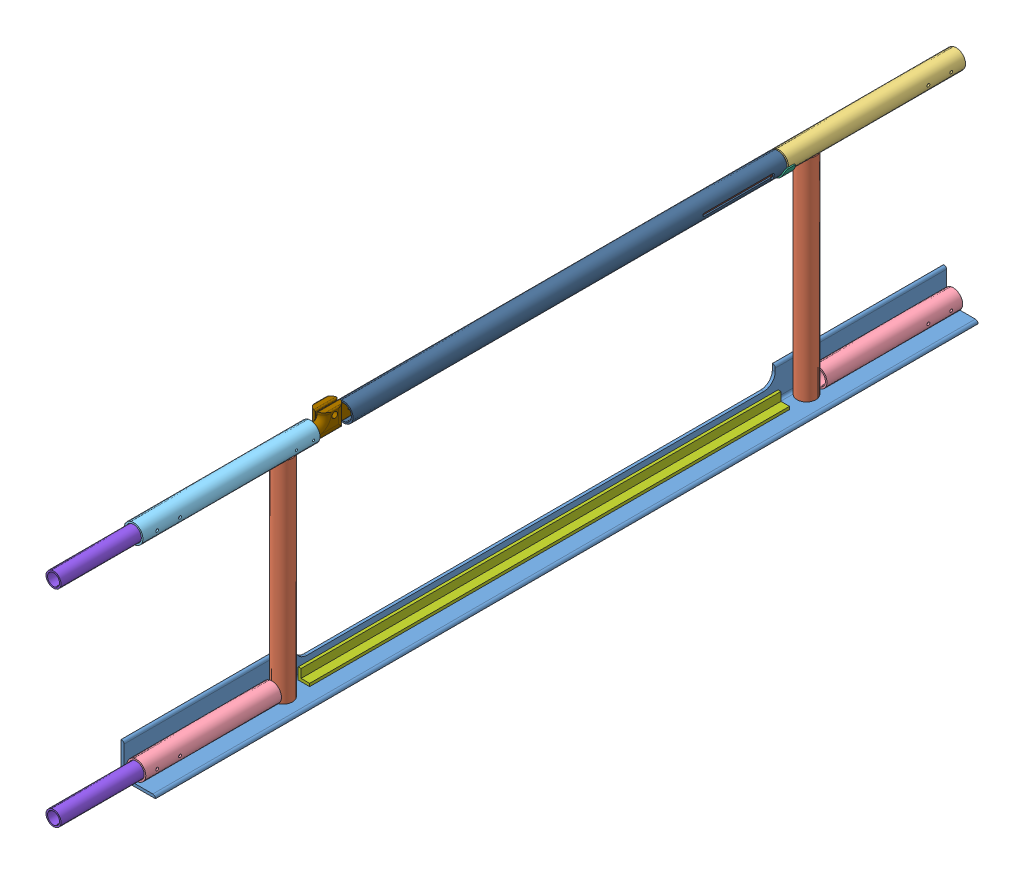
SolidWorks assembly FE-00029_ASM, configuration Default. Lengths in mm.
Overall size (76.2 519.84 2006.6).
16 component instances, 11 part files, 0 mates.
Components (placement in the parent):
- FE-00006_ASM-1: FE-00006_ASM [Default] at origin size (76.2 507.65 1828.8)
  - FE-00006-01-1: FE-00006-01 [Default] at origin size (76.2 76.2 1828.8)
  - FE-00006-10-1: FE-00006-10 [Default] at (27.432 6.35 1496.2188) size (42.16 471.23 42.16)
  - FE-00006-03-1: FE-00006-03 [Default] at (27.432 486.5688 393.7) x (1 0 0) z (0 0 -1) size (42.16 42.16 393.7)
  - FE-00006-02-1: FE-00006-02 [Default] at (27.432 27.432 1520.825) size (42.16 42.16 301.62)
  - FE-00006-02-2: FE-00006-02 [Default] at (27.432 27.432 307.975) x (1 0 0) z (0 0 -1) size (42.16 42.16 301.62)
  - FE-00006-10-2: FE-00006-10 [Default] at (27.432 6.35 332.5876) size (42.16 471.23 42.16)
  - FE-00006-05-1: FE-00006-05 [Default] at (27.432 486.5688 1435.1) size (42.16 42.16 393.7)
  - FE-00006-08-1: FE-00006-08 [Default] at (27.432 486.5688 381) size (48.26 22.22 25.4)
  - FE-00006-09-1: FE-00006-09 [Default] at (12.7 6.35 381) size (25.4 25.4 1066.8)
- FE-00026-1: FE-00026 [Default] at (27.432 27.432 1651) size (33.4 33.4 355.6)
- FE-00026-2: FE-00026 [Default] at (27.432 486.5688 1651) size (33.4 33.4 355.6)
- FE-00027-1: FE-00027 [Default] at (29.0202 469.0397 1500.1875) x (1 0.000041 0) z (0 0.000003 1) size (15.88 50.56 126.92)
- FE-00027-2: FE-00027 [Default] at (25.8452 469.039 1296.9875) x (-1 -0.000041 0) z (0 -0.000003 -1) size (15.88 50.56 126.92)
- FE-00028-1: FE-00028 [Default] at (27.432 486.5728 879.1575) x (0 -0.000003 -1) z (1 0.000041 0) size (965.2 42.16 42.16)
- FE-00031-1: FE-00031 [Default] at (27.432 486.5717 428.3075) x (0 0.000003 1) z (-1 -0.000041 0) size (304.8 33.4 33.4)
